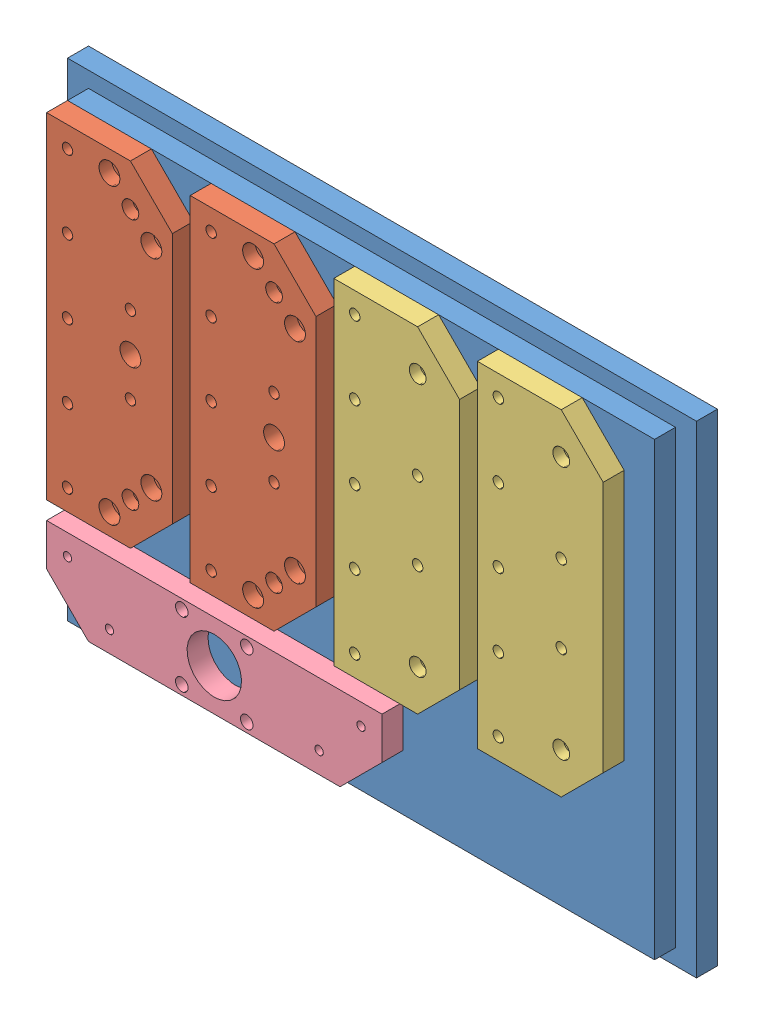
SolidWorks assembly Corte01, configuration Valor predeterminado. Lengths in mm.
Overall size (300 230 30).
6 component instances, 4 part files, 16 mates.
Components (placement in the parent):
- Mesa-1: Mesa [Valor predeterminado] at (-55.4313 -7.8261 -10) size (300 230 20)
- GuiaInferior1-2: GuiaInferior1 [Valor predeterminado] at (-195.3713 57.2164 10) x (-1 0 0) z (0 0 1) size (60 160 10)
- GuiaInferior1-3: GuiaInferior1 [Valor predeterminado] at (-126.8713 57.2164 10) x (-1 0 0) z (0 0 1) size (60 160 10)
- GuiaSuperior-1: GuiaSuperior [Valor predeterminado] at (-58.3713 52.234 10) x (-1 0 0) z (0 0 1) size (60 160 10)
- GuiaSuperior-2: GuiaSuperior [Valor predeterminado] at (10.1287 52.234 10) x (-1 0 0) z (0 0 1) size (60 160 10)
- SuporteMotor-1: SuporteMotor [Valor predeterminado] at (-147.8669 -68.8261 10) x (0 -1 0) z (0 0 1) size (40 160 10)
Mates (geometry in assembly coordinates):
- Coincidente4: coincident anti-aligned: plane of Mesa-1 through (-55.4313 -7.8261 10) normal (0 0 1); plane of GuiaInferior1-2 through (-195.3713 57.2164 10) normal (0 0 -1)
- Coincidente7: coincident aligned: plane of Mesa-1 through (-195.4313 99.6739 10) normal (0 1 0); plane of GuiaInferior1-2 through (-195.3713 99.6739 20) normal (0 1 0)
- Coincidente8: coincident aligned: plane of Mesa-1 through (-195.4313 -115.3261 10) normal (-1 0 0); plane of GuiaInferior1-2 through (-195.4313 57.2164 20) normal (-1 0 0)
- Coincidente9: coincident aligned: plane of Mesa-1 through (-195.4313 99.6739 10) normal (0 1 0); plane of GuiaInferior1-3 through (-126.8713 99.6739 20) normal (0 1 0)
- Distância2: distance = 8.5 mm anti-aligned: plane of GuiaInferior1-2 through (-135.4313 57.2164 20) normal (1 0 0); plane of GuiaInferior1-3 through (-126.9313 57.2164 20) normal (-1 0 0)
- Coincidente11: coincident anti-aligned: plane of Mesa-1 through (-55.4313 -7.8261 10) normal (0 0 1); plane of GuiaInferior1-3 through (-126.8713 57.2164 10) normal (0 0 -1)
- Coincidente12: coincident anti-aligned: plane of Mesa-1 through (-55.4313 -7.8261 10) normal (0 0 1); plane of GuiaSuperior-1 through (-58.3713 52.234 10) normal (0 0 -1)
- Coincidente13: coincident aligned: plane of Mesa-1 through (-195.4313 99.6739 10) normal (0 1 0); plane of GuiaSuperior-1 through (-58.3713 99.6739 20) normal (0 1 0)
- Distância3: distance = 8.5 mm anti-aligned: plane of GuiaInferior1-3 through (-66.9313 57.2164 20) normal (1 0 0); plane of GuiaSuperior-1 through (-58.4313 52.234 20) normal (-1 0 0)
- Coincidente16: coincident anti-aligned: plane of Mesa-1 through (-55.4313 -7.8261 10) normal (0 0 1); plane of GuiaSuperior-2 through (10.1287 52.234 10) normal (0 0 -1)
- Coincidente17: coincident aligned: plane of Mesa-1 through (-195.4313 99.6739 10) normal (0 1 0); plane of GuiaSuperior-2 through (10.1287 99.6739 20) normal (0 1 0)
- Distância4: distance = 8.5 mm anti-aligned: plane of GuiaSuperior-1 through (1.5687 52.234 20) normal (1 0 0); plane of GuiaSuperior-2 through (10.0687 52.234 20) normal (-1 0 0)
- Coincidente19: coincident anti-aligned: plane of Mesa-1 through (-55.4313 -7.8261 10) normal (0 0 1); plane of SuporteMotor-1 through (-147.8669 -68.8261 10) normal (0 0 -1)
- Perpendicular1: perpendicular: plane of Mesa-1 through (-195.4313 -115.3261 10) normal (-1 0 0); plane of SuporteMotor-1 through (-147.8669 -68.8261 20) normal (0 1 0)
- Distância5: distance = 8.5 mm anti-aligned: plane of GuiaInferior1-2 through (-195.3713 -60.3261 20) normal (0 -1 0); plane of SuporteMotor-1 through (-147.8669 -68.8261 20) normal (0 1 0)
- Coincidente22: coincident aligned: plane of Mesa-1 through (-195.4313 -115.3261 10) normal (-1 0 0); plane of SuporteMotor-1 through (-195.4313 -68.8261 20) normal (-1 0 0)
